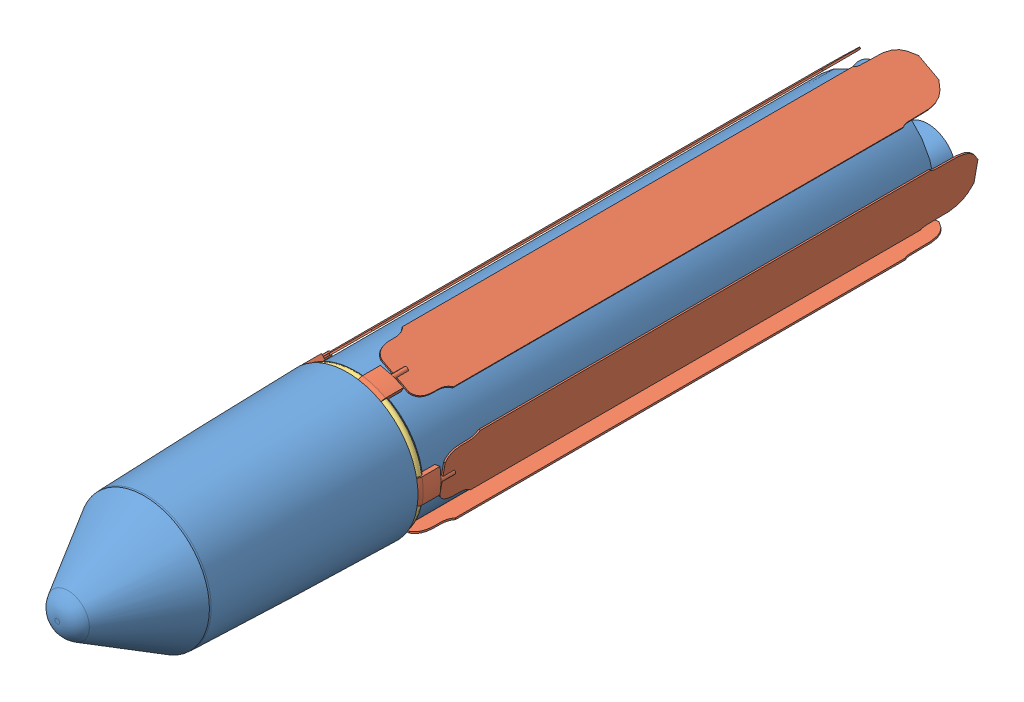
SolidWorks assembly 舱室, configuration 默认. Lengths in mm.
Overall size (104.42 109.22 586.09).
7 component instances, 3 part files, 0 mates.
Components (placement in the parent):
- r-1: r [默认] at (-4.1455 10.1153 -75.4152) size (102.41 102.31 578)
- huan1-1: huan1 [默认] at origin size (10.38 39.13 386.08)
- huan1-2: huan1 [默认] at (-12.4847 3.0469 0) x (0.309017 -0.951057 0) z (0 0 1) size (10.38 39.13 386.08)
- huan1-3: huan1 [默认] at (-13.445 15.8621 0) x (-0.809017 -0.587785 0) z (0 0 1) size (10.38 39.13 386.08)
- huan1-4: huan1 [默认] at (-1.5537 20.7354 0) x (-0.809017 0.587785 0) z (0 0 1) size (10.38 39.13 386.08)
- huan1-5: huan1 [默认] at (6.7557 10.9321 0) x (0.309017 0.951057 0) z (0 0 1) size (10.38 39.13 386.08)
- huan2-1: huan2 [默认] at origin size (95.19 95.19 5)
